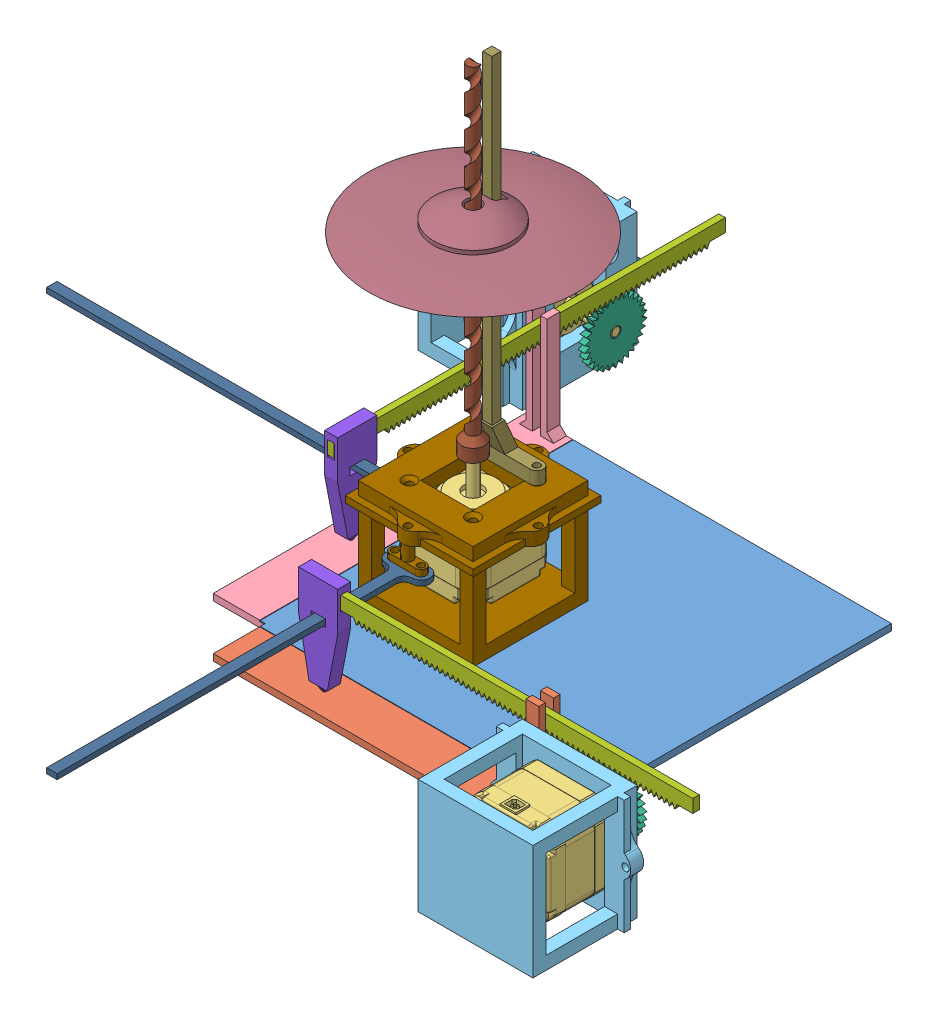
SolidWorks assembly FullAssembly, configuration Default. Lengths in mm.
Overall size (385.06 237.72 385.06).
20 component instances, 13 part files, 57 mates.
Components (placement in the parent):
- BasePlate-1: BasePlate [Default] at (-31.6164 84.1284 163.9089) size (154.94 3.17 154.94)
- FlangeX-1: FlangeX [Default] at (-31.6164 84.1284 189.3089) size (152.4 53.98 25.4)
- 6627T650_POSITION-CONTROL DC MOTOR-1: 6627T650_POSITION-CONTROL DC MOTOR [6627T65] at (-68.3829 112.0744 -19.6121) x (0 0 -1) z (1 0 0) size (42.42 42.97 53.59)
- 6627T650_POSITION-CONTROL DC MOTOR-2: 6627T650_POSITION-CONTROL DC MOTOR [6627T65] at (151.9046 112.0744 200.6754) x (-1 0 0) z (0 0 -1) size (42.42 42.97 53.59)
- 6627T650_POSITION-CONTROL DC MOTOR-3: 6627T650_POSITION-CONTROL DC MOTOR [6627T65] at (12.5796 134.9284 107.0009) x (0 0 -1) z (0 1 0) size (42.42 42.97 53.59)
- FlangeY-1: FlangeY [Default] at (-57.0164 84.1284 163.9089) x (0 0 1) z (-1 0 0) size (152.4 53.98 25.4)
- MotorCarriage-2: MotorCarriage [Default] at (123.9586 140.0084 245.1254) x (1 0 0) z (0 1 0) size (68.58 50.8 55.88)
- MotorCarriage-3: MotorCarriage [Default] at (-112.8329 140.0084 -47.5461) x (0 0 1) z (0 1 0) size (68.58 50.8 55.88)
- AxisGear-1: AxisGear [Default] at (151.9046 112.0744 176.7994) size (30.19 30.35 3.17)
- AxisGear-2: AxisGear [Default] at (-44.5069 112.0744 -19.6121) x (0 0.406737 0.913545) z (-1 0 0) size (30.19 30.35 3.17)
- Axis-1: Axis [Default] at (192.5446 133.6007 176.7994) x (-1 0 0) z (0 0 1) size (190.5 8.89 3.17)
- Axis-2: Axis [Default] at (-47.6819 133.6007 -72.9521) x (0 0 1) z (1 0 0) size (190.5 8.89 3.17)
- XYSlider-1: XYSlider [Default] at (2.0446 136.7757 175.0849) size (19.05 49.28 6.35)
- XYSlider-2: XYSlider [Default] at (-42.7924 136.7757 98.4979) x (0 0 1) z (-1 0 0) size (19.05 49.28 6.35)
- MotorCarriageZ-1: MotorCarriageZ [Default] at (40.5256 90.4784 134.9469) x (0 0 -1) z (1 0 0) size (68.58 53.97 68.58)
- ZAttachment-1: ZAttachment [Default] at (10.0456 118.8687 312.1119) size (21.59 2.54 177.8)
- ZAttachment-2: ZAttachment [Default] at (-192.5194 118.8687 104.4669) x (0 0 1) z (-1 0 0) size (21.59 2.54 177.8)
- ZAxis-1: ZAxis [Default] at (12.5796 152.4544 107.0009) x (0.999638 0 -0.026923) z (0.026923 0 0.999638) size (11.43 169.4 11.43)
- ZStabilizer-1: ZStabilizer [Default] at (9.4166 147.6284 94.6819) x (0 0 -1) z (1 0 0) size (12.7 176.4 37.34)
- MovingPart-1: MovingPart [Default] at (12.5796 239.0294 107.0009) x (-1 0 0) z (0 0 -1) size (101.6 18.18 101.6)
Mates (geometry in assembly coordinates):
- Coincident6: coincident anti-aligned: plane of BasePlate-1 through (-31.6164 86.6684 163.9089) normal (0 -1 0); plane of Flange-1 through (-31.6164 86.6684 189.3089) normal (0 1 0)
- Coincident7: coincident aligned: plane of BasePlate-1 through (120.7836 87.3034 163.9089) normal (1 0 0); plane of Flange-1 through (120.7836 87.3034 189.3089) normal (1 0 0)
- Coincident8: coincident anti-aligned: plane of BasePlate-1 through (-31.6164 87.3034 163.9089) normal (0 0 1); plane of Flange-1 through (-31.6164 87.3034 163.9089) normal (0 0 -1)
- Coincident9: coincident anti-aligned: plane of BasePlate-1 through (-31.6164 87.3034 163.9089) normal (-1 0 0); plane of FlangeY-1 through (-31.6164 87.3034 163.9089) normal (1 0 0)
- Coincident10: coincident aligned: plane of BasePlate-1 through (-31.6164 87.3034 163.9089) normal (0 1 0); plane of FlangeY-1 through (-57.0164 87.3034 163.9089) normal (0 1 0)
- Coincident11: coincident aligned: plane of BasePlate-1 through (-31.6164 87.3034 11.5089) normal (0 0 -1); plane of FlangeY-1 through (-57.0164 87.3034 11.5089) normal (0 0 -1)
- Coincident12: coincident anti-aligned: plane of 6627T650_POSITION-CONTROL DC MOTOR-2 through (151.9046 112.0744 200.6754) normal (0 0 -1); plane of MotorCarriage-2 through (130.3086 84.1284 200.6754) normal (0 0 1)
- Concentric1: concentric aligned: circle of 6627T650_POSITION-CONTROL DC MOTOR-2; circle of MotorCarriage-2
- Coincident13: coincident anti-aligned: plane of 6627T650_POSITION-CONTROL DC MOTOR-1 through (-68.3829 112.0744 -19.6121) normal (1 0 0); plane of MotorCarriage-3 through (-68.3829 84.1284 -41.1961) normal (-1 0 0)
- Concentric7: concentric aligned: circle of 6627T650_POSITION-CONTROL DC MOTOR-1; circle of MotorCarriage-3
- Coincident14: coincident aligned: plane of FlangeX-1 through (-31.6164 84.1284 189.3089) normal (0 -1 0); plane of MotorCarriage-2 through (123.9586 84.1284 194.3254) normal (0 -1 0)
- Coincident15: coincident aligned: plane of FlangeY-1 through (-57.0164 84.1284 163.9089) normal (0 -1 0); plane of MotorCarriage-3 through (-62.0329 84.1284 -47.5461) normal (0 -1 0)
- Concentric8: concentric anti-aligned: circle of 6627T650_POSITION-CONTROL DC MOTOR-2; circle of AxisGear-1
- Coincident16: coincident aligned: plane of 6627T650_POSITION-CONTROL DC MOTOR-2 through (151.9046 114.5699 176.7994) normal (0 0 -1); plane of AxisGear-1 through (151.9046 112.0744 176.7994) normal (0 0 -1)
- Concentric9: concentric anti-aligned: circle of 6627T650_POSITION-CONTROL DC MOTOR-1; circle of AxisGear-2
- Coincident18: coincident aligned: plane of 6627T650_POSITION-CONTROL DC MOTOR-1 through (-44.5069 114.5699 -19.6121) normal (1 0 0); plane of AxisGear-2 through (-44.5069 112.0744 -19.6121) normal (1 0 0)
- Coincident19: coincident anti-aligned: plane of FlangeY-1 through (-47.6819 87.3034 17.8589) normal (1 0 0); plane of AxisGear-2 through (-47.6819 112.0744 -19.6121) normal (-1 0 0)
- Coincident20: coincident aligned: plane of FlangeX-1 through (-31.6164 84.1284 189.3089) normal (0 -1 0); plane of MotorCarriage-2 through (123.9586 84.1284 194.3254) normal (0 -1 0)
- Coincident21: coincident anti-aligned: plane of FlangeX-1 through (114.4336 87.3034 179.9744) normal (0 0 -1); plane of AxisGear-1 through (151.9046 112.0744 179.9744) normal (0 0 1)
- Coincident25: coincident aligned: plane of AxisGear-1 through (151.9046 112.0744 179.9744) normal (0 0 1); plane of Axis-1 through (192.5446 133.6007 179.9744) normal (0 0 1)
- Coincident26: coincident anti-aligned: plane of AxisGear-1 through (153.1746 124.7107 179.9744) normal (0.894427 0.447214 0); plane of Axis-1 through (151.9046 127.2507 173.2073) normal (-0.894427 -0.447214 0)
- Coincident27: coincident anti-aligned: line of AxisGear-1 through (151.9046 127.2507 179.9744) axis (0 0 -1); line of Axis-1 through (151.9046 127.2507 176.7994) axis (0 0 1)
- Parallel1: parallel aligned: plane of 6627T650_POSITION-CONTROL DC MOTOR-2 through (138.0208 133.2834 208.2446) normal (0 1 0); plane of MotorCarriage-2 through (123.9586 140.0084 194.3254) normal (0 1 0)
- Parallel2: parallel aligned: plane of 6627T650_POSITION-CONTROL DC MOTOR-1 through (-75.9521 133.2834 -33.4959) normal (0 1 0); plane of MotorCarriage-3 through (-62.0329 140.0084 -47.5461) normal (0 1 0)
- Parallel3: parallel aligned: plane of FlangeX-1 through (114.4336 138.1034 183.1494) normal (0 1 0); plane of Axis-1 through (192.5446 133.6007 179.9744) normal (0 1 0)
- Parallel4: parallel aligned: plane of FlangeY-1 through (-50.8569 138.1034 17.8589) normal (0 1 0); plane of Axis-2 through (-44.5069 134.2669 -73.2852) normal (0 1 0)
- Distance1: distance = 3.175 mm aligned: plane of Axis-2 through (-44.5069 133.6007 -72.9521) normal (0 1 0); plane of XYSlider-2 through (-49.1424 136.7757 98.4979) normal (0 1 0)
- Parallel6: parallel anti-aligned: plane of Axis-2 through (-44.5069 134.2669 -73.2852) normal (0 1 0); plane of XYSlider-2 through (-44.2529 134.2669 117.2148) normal (0 -1 0)
- Coincident35: coincident anti-aligned: plane of Axis-2 through (-47.6819 134.2669 -73.2852) normal (-1 0 0); plane of XYSlider-2 through (-47.6819 134.2669 117.2148) normal (1 0 0)
- Coincident36: coincident aligned: plane of Axis-2 through (-44.5069 134.2669 117.2148) normal (0 0 1); plane of XYSlider-2 through (-49.1424 137.4419 117.2148) normal (0 0 1)
- Coincident37: coincident anti-aligned: plane of Axis-1 through (192.5446 133.6007 179.9744) normal (0 0 1); plane of XYSlider-1 through (21.0946 133.6007 179.9744) normal (0 0 -1)
- Coincident39: coincident aligned: plane of Axis-1 through (2.0446 133.6007 179.9744) normal (-1 0 0); plane of XYSlider-1 through (2.0446 136.7757 181.4349) normal (-1 0 0)
- Coincident40: coincident anti-aligned: plane of Axis-1 through (192.5446 133.6007 179.9744) normal (0 1 0); plane of XYSlider-1 through (21.0946 133.6007 176.5454) normal (0 -1 0)
- Coincident43: coincident anti-aligned: plane of 6627T650_POSITION-CONTROL DC MOTOR-3 through (12.5796 134.9284 106.6678) normal (0 1 0); plane of MotorCarriageZ-1 through (-15.3544 134.9284 128.2638) normal (0 -1 0)
- Concentric13: concentric anti-aligned: circle of 6627T650_POSITION-CONTROL DC MOTOR-3; circle of MotorCarriageZ-1
- Parallel9: parallel aligned: plane of 6627T650_POSITION-CONTROL DC MOTOR-3 through (-8.5024 -499865.0716 119.0933) normal (-1 0 0); plane of MotorCarriageZ-1 through (-18.5294 90.4784 134.6138) normal (-1 0 0)
- Distance2: distance = 3.175 mm anti-aligned: plane of MotorCarriageZ-1 through (40.5256 90.4784 134.9469) normal (0 -1 0); plane of BasePlate-1 through (-31.6164 87.3034 163.9089) normal (0 1 0)
- Coincident46: coincident anti-aligned: plane of XYSlider-1 through (8.0136 121.4087 175.0849) normal (0 -1 0); plane of ZAttachment-1 through (6.2356 121.4087 146.6788) normal (0 1 0)
- Coincident47: coincident anti-aligned: plane of XYSlider-1 through (15.1256 117.7257 175.0849) normal (-1 0 0); plane of ZAttachment-1 through (15.1256 121.4087 311.7788) normal (1 0 0)
- Concentric15: concentric anti-aligned: circle of MotorCarriageZ-1; circle of ZAttachment-1
- Concentric16: concentric anti-aligned: cylinder of MotorCarriageZ-1 through (6.2356 121.3394 138.4238) axis (0 1 0) radius 1.651; cylinder of ZAttachment-1 through (6.2356 121.4087 138.4238) axis (0 -1 0) radius 1.651
- Coincident49: coincident anti-aligned: plane of XYSlider-2 through (-42.7924 122.0749 104.1338) normal (0 -1 0); plane of ZAttachment-2 through (-27.4194 122.0749 100.3238) normal (0 1 0)
- Coincident50: coincident anti-aligned: plane of XYSlider-2 through (-42.7924 118.3919 104.1338) normal (0 0 1); plane of ZAttachment-2 through (-192.5194 122.0749 104.1338) normal (0 0 -1)
- Concentric17: concentric anti-aligned: circle of MotorCarriageZ-1; circle of ZAttachment-2
- Concentric18: concentric anti-aligned: circle of MotorCarriageZ-1; circle of ZAttachment-2
- Concentric19: concentric anti-aligned: circle of 6627T650_POSITION-CONTROL DC MOTOR-3; circle of ZAxis-1
- Coincident51: coincident anti-aligned: plane of 6627T650_POSITION-CONTROL DC MOTOR-3 through (10.084 158.8044 106.6678) normal (0 1 0); plane of ZAxis-1 through (12.5796 158.8044 106.6678) normal (0 -1 0)
- Parallel10: parallel aligned: plane of MotorCarriageZ-1 through (40.5256 141.2784 78.7338) normal (0 0 -1); plane of ZStabilizer-1 through (28.0856 141.2784 87.9988) normal (0 0 -1)
- Concentric20: concentric aligned: cylinder of MotorCarriageZ-1 through (28.0856 60.9073 91.1738) axis (0 1 0) radius 1.75; cylinder of ZStabilizer-1 through (28.0856 141.2784 91.1738) axis (0 1 0) radius 1.651
- Coincident53: coincident anti-aligned: plane of MotorCarriageZ-1 through (40.5256 141.2784 134.6138) normal (0 1 0); plane of ZStabilizer-1 through (28.0856 141.2784 91.1738) normal (0 -1 0)
- Parallel11: parallel anti-aligned: plane of ZStabilizer-1 through (14.8141 317.6814 95.3013) normal (0 0 -1); plane of MovingPart-1 through (9.4046 258.0794 92.6978) normal (0 0 1)
- Coincident54: coincident anti-aligned: plane of FlangeX-1 through (120.7836 87.3034 189.3089) normal (1 0 0); plane of MotorCarriage-2 through (120.7836 74.0881 200.6754) normal (-1 0 0)
- Coincident55: coincident anti-aligned: plane of FlangeY-1 through (-57.0164 87.3034 11.5089) normal (0 0 -1); plane of MotorCarriage-3 through (-68.3829 74.0881 11.5089) normal (0 0 1)
- Concentric21: concentric aligned: circle of ZAxis-1; circle of MovingPart-1
- Coincident56: coincident aligned: plane of AxisGear-2 through (-44.5069 112.0744 -19.6121) normal (1 0 0); plane of Axis-2 through (-44.5069 133.6007 -72.9521) normal (1 0 0)
- Coincident57: coincident anti-aligned: plane of AxisGear-2 through (-47.6819 124.7107 -18.3421) normal (0 0.447214 0.894427); plane of Axis-2 through (-51.274 124.7107 -18.3421) normal (0 -0.447214 -0.894427)
- Coincident58: coincident aligned: line of AxisGear-2 through (-47.6819 124.7107 -18.3421) axis (1 0 0); line of Axis-2 through (-47.6819 124.7107 -18.3421) axis (1 0 0)
